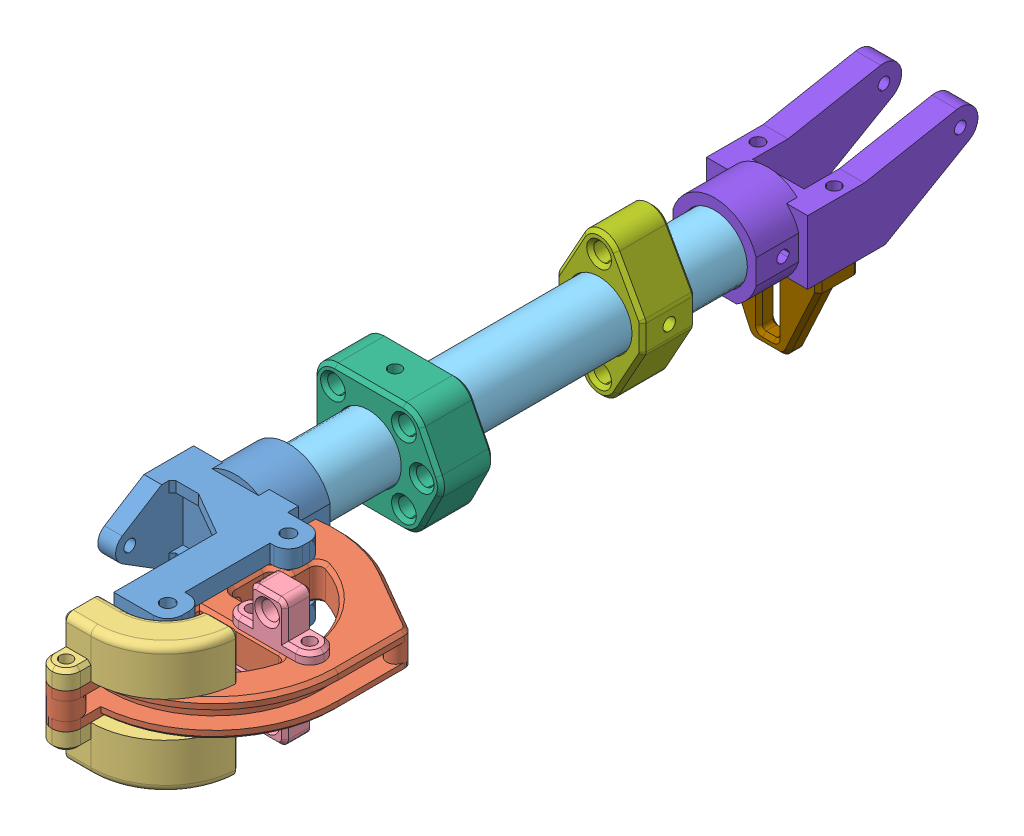
SolidWorks assembly link_leg, configuration ﾃﾞﾌｫﾙﾄ. Lengths in mm.
Overall size (70.45 52.25 265.64).
11 component instances, 9 part files, 26 mates.
Components (placement in the parent):
- shoulder_joint_connector-1: shoulder_joint_connector [outer] at origin size (39.7 24.5 59)
- shoulder_joint_circle-1: shoulder_joint_circle [ﾃﾞﾌｫﾙﾄ] at (19.95 5 26) x (1 0 0) z (0 -1 0) size (40 79.64 10)
- shoulder_fromknee_middle_curve-1: shoulder_fromknee_middle_curve [mirror] at (18.95 5 58.641) x (0 0 1) z (0 1 0) size (28 28.97 13)
- shoulder_fromknee_middle_curve-2: shoulder_fromknee_middle_curve [ﾃﾞﾌｫﾙﾄ] at (18.95 -5 58.641) x (0 0 1) z (0 1 0) size (28 28.97 13)
- shoulder_fromknee_middle-1: shoulder_fromknee_middle [ﾃﾞﾌｫﾙﾄ] at (38.95 5 26) x (1 0 0) z (0 -1 0) size (24 8 13)
- shoulder_fromknee_middle-2: shoulder_fromknee_middle [ﾃﾞﾌｫﾙﾄ] at (38.95 -5 26) x (-1 0 0) z (0 1 0) size (24 8 13)
- pipe_leg-1: pipe_leg [ﾃﾞﾌｫﾙﾄ] x (1 0 0) z (0 0 -1) size (18 18 150)
- wire_end_5_small-1: wire_end_5_small [ﾃﾞﾌｫﾙﾄ] at (0 0 -45) x (0 -1 0) z (0 0 1) size (31 35.94 15)
- wire_end_small-1: wire_end_small [ﾃﾞﾌｫﾙﾄ] at (0 0 -110) x (0 1 0) z (0 0 1) size (40.5 24.5 15)
- knee2-1: knee2 [outer] at (0 0 -135) x (-1 0 0) z (0 0 -1) size (28.5 25.58 60)
- knee_support-1: knee_support [ﾃﾞﾌｫﾙﾄ] at (0 -9 -158) x (-1 0 0) z (0 -1 0) size (28.5 11 23)
Mates (geometry in assembly coordinates):
- 同心円2: concentric aligned: cylinder of shoulder_joint_connector-1 through (19.95 10.35 5) axis (0 -1 0) radius 1.9; cylinder of shoulder_joint_circle-1 through (19.95 5 5) axis (0 -1 0) radius 1.75
- 同心円3: concentric aligned: cylinder of shoulder_joint_connector-1 through (19.95 10.35 39) axis (0 -1 0) radius 1.9; cylinder of shoulder_joint_circle-1 through (19.95 5 39) axis (0 -1 0) radius 1.75
- 幅1: width anti-aligned: plane of shoulder_joint_connector-1 through (24.95 -5.35 0) normal (0 1 0); plane of shoulder_joint_circle-1 through (24.95 5.35 0) normal (0 -1 0); plane of shoulder_joint_connector-1 through (19.95 -5 26) normal (0 -1 0); plane of shoulder_joint_circle-1 through (19.95 5 26) normal (0 1 0)
- 同心円5: concentric anti-aligned: cylinder of shoulder_joint_circle-1 through (18.95 -2.5 66.641) axis (0 -1 0) radius 1.75; cylinder of shoulder_fromknee_middle_curve-1 through (18.95 5 66.641) axis (0 1 0) radius 1.75
- 同心円6: concentric anti-aligned: cylinder of shoulder_joint_circle-1 through (18.95 5 50.641) axis (0 -1 0) radius 1.75; cylinder of shoulder_fromknee_middle_curve-1 through (18.95 5 50.641) axis (0 1 0) radius 1.75
- 一致1: coincident anti-aligned: plane of shoulder_joint_circle-1 through (19.95 5 26) normal (0 1 0); plane of shoulder_fromknee_middle_curve-1 through (22.95 5 46.641) normal (0 -1 0)
- 同心円7: concentric aligned: cylinder of shoulder_joint_circle-1 through (18.95 -2.5 66.641) axis (0 -1 0) radius 1.75; cylinder of shoulder_fromknee_middle_curve-2 through (18.95 -5 66.641) axis (0 -1 0) radius 1.75
- 同心円8: concentric aligned: cylinder of shoulder_joint_circle-1 through (18.95 5 50.641) axis (0 -1 0) radius 1.75; cylinder of shoulder_fromknee_middle_curve-2 through (18.95 -5 50.641) axis (0 -1 0) radius 1.75
- 一致2: coincident anti-aligned: plane of shoulder_joint_circle-1 through (19.95 -5 26) normal (0 -1 0); plane of shoulder_fromknee_middle_curve-2 through (22.95 -5 46.641) normal (0 1 0)
- 同心円9: concentric anti-aligned: cylinder of shoulder_joint_circle-1 through (46.95 5 26) axis (0 -1 0) radius 1.75; cylinder of shoulder_fromknee_middle-1 through (46.95 5 26) axis (0 1 0) radius 1.75
- 同心円10: concentric anti-aligned: cylinder of shoulder_joint_circle-1 through (30.95 5 26) axis (0 -1 0) radius 1.75; cylinder of shoulder_fromknee_middle-1 through (30.95 5 26) axis (0 1 0) radius 1.75
- 一致3: coincident anti-aligned: plane of shoulder_joint_circle-1 through (19.95 5 26) normal (0 1 0); plane of shoulder_fromknee_middle-1 through (26.95 5 30) normal (0 -1 0)
- 同心円11: concentric aligned: cylinder of shoulder_joint_circle-1 through (30.95 5 26) axis (0 -1 0) radius 1.75; cylinder of shoulder_fromknee_middle-2 through (30.95 -5 26) axis (0 -1 0) radius 1.75
- 同心円12: concentric aligned: cylinder of shoulder_joint_circle-1 through (46.95 5 26) axis (0 -1 0) radius 1.75; cylinder of shoulder_fromknee_middle-2 through (46.95 -5 26) axis (0 -1 0) radius 1.75
- 一致4: coincident anti-aligned: plane of shoulder_joint_circle-1 through (19.95 -5 26) normal (0 -1 0); plane of shoulder_fromknee_middle-2 through (50.95 -5 30) normal (0 1 0)
- 同心円15: concentric anti-aligned: cylinder of pipe_leg-1 through (0 0 -150) axis (0 0 1) radius 9; cylinder of wire_end_5_small-1 through (0 0 -37.5) axis (0 0 -1) radius 9.25
- 同心円16: concentric aligned: cylinder of pipe_leg-1 through (0 9 -45) axis (0 -1 0) radius 1.75; cylinder of wire_end_5_small-1 through (0 15.5 -45) axis (0 -1 0) radius 1.75
- 同心円17: concentric anti-aligned: cylinder of pipe_leg-1 through (0 0 -150) axis (0 0 1) radius 9; cylinder of wire_end_small-1 through (0 0 -102.5) axis (0 0 -1) radius 9.25
- 同心円18: concentric anti-aligned: cylinder of pipe_leg-1 through (-9 0 -110) axis (1 0 0) radius 1.75; cylinder of wire_end_small-1 through (12.25 0 -110) axis (-1 0 0) radius 1.75
- 一致5: coincident anti-aligned: plane of knee2-1 through (14.25 -9 -153) normal (0 -1 0); plane of knee_support-1 through (0 -9 -158) normal (0 1 0)
- 同心円21: concentric aligned: cylinder of knee2-1 through (10.75 -9 -158) axis (0 1 0) radius 1.8; cylinder of knee_support-1 through (10.75 -12 -158) axis (0 1 0) radius 1.65
- 同心円22: concentric aligned: cylinder of knee2-1 through (-10.75 -9 -158) axis (0 1 0) radius 1.8; cylinder of knee_support-1 through (-10.75 -12 -158) axis (0 1 0) radius 1.65
- 同心円23: concentric aligned: cylinder of shoulder_joint_connector-1 through (0 0 -15) axis (0 0 1) radius 12.25; cylinder of pipe_leg-1 through (0 0 -150) axis (0 0 1) radius 9
- 同心円24: concentric aligned: cylinder of shoulder_joint_connector-1 through (-14.75 0 -7.5) axis (1 0 0) radius 1.65; cylinder of pipe_leg-1 through (-9 0 -7.5) axis (1 0 0) radius 1.75
- 同心円25: concentric anti-aligned: cylinder of pipe_leg-1 through (-9 0 -142.5) axis (1 0 0) radius 1.75; cylinder of knee2-1 through (14.25 0 -142.5) axis (-1 0 0) radius 1.65
- 同心円26: concentric anti-aligned: cylinder of pipe_leg-1 through (0 0 -150) axis (0 0 1) radius 9; cylinder of knee2-1 through (0 0 -135) axis (0 0 -1) radius 9.25
